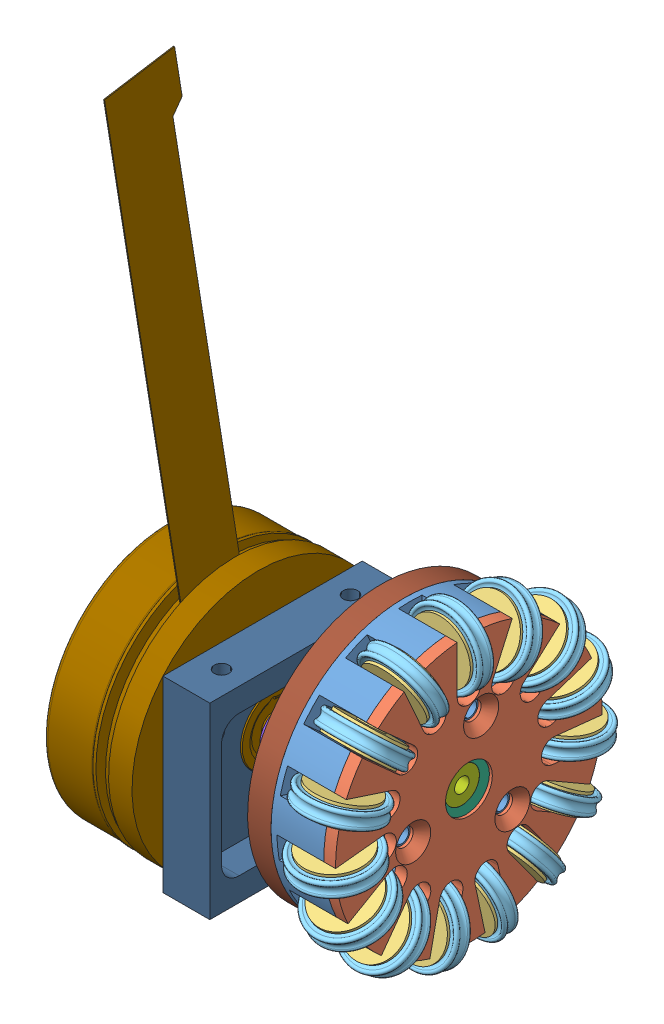
SolidWorks assembly drive_right, configuration Default. Lengths in mm.
Overall size (56.39 137.4 77.93).
69 component instances, 11 part files, 22 mates.
Components (placement in the parent):
- wheel_hub_flat_back-1: wheel_hub_flat_back [Default] at (-31.4027 -2.3485 15.5279) size (9 45.5 45.5)
- wheel_cover-1: wheel_cover [Default] at (-22.4027 -2.3485 15.5279) size (2 45.41 45.5)
- wheel_roller_asm-1: wheel_roller_asm [Default] at (-3.0698 37.2715 -2.2573) x (0.742932 0.669367 0) z (0 0 1) size (12.8 12.8 6)
  - wheel_roller_hub-1: wheel_roller_hub [Default] at (-28.6925 -1.096 17.7852) size (10.4 10.4 3.8)
  - wheel_roller_pin-1: wheel_roller_pin [Default] at (-28.6925 -1.096 14.7852) size (2.5 2.5 6)
  - xring_109-1: xring_109 [Default] at (-28.6925 -1.096 17.7852) size (12.8 12.8 2.6)
- wheel_roller_asm-2: wheel_roller_asm [Default] at (-3.0698 41.0801 15.3952) x (0.742932 0.611497 0.272256) z (0 -0.406737 0.913545) size (12.8 12.8 6)
  - wheel_roller_hub-1: wheel_roller_hub [Default] at (-28.6925 -1.096 17.7852) size (10.4 10.4 3.8)
  - wheel_roller_pin-1: wheel_roller_pin [Default] at (-28.6925 -1.096 14.7852) size (2.5 2.5 6)
  - xring_109-1: xring_109 [Default] at (-28.6925 -1.096 17.7852) size (12.8 12.8 2.6)
- wheel_roller_asm-3: wheel_roller_asm [Default] at (-3.0698 37.3795 33.0707) x (0.742932 0.447894 0.497437) z (0 -0.743145 0.669131) size (12.8 12.8 6)
  - wheel_roller_hub-1: wheel_roller_hub [Default] at (-28.6925 -1.096 17.7852) size (10.4 10.4 3.8)
  - wheel_roller_pin-1: wheel_roller_pin [Default] at (-28.6925 -1.096 14.7852) size (2.5 2.5 6)
  - xring_109-1: xring_109 [Default] at (-28.6925 -1.096 17.7852) size (12.8 12.8 2.6)
- wheel_roller_asm-4: wheel_roller_asm [Default] at (-3.0698 26.8095 47.7129) x (0.742932 0.206846 0.636606) z (0 -0.951057 0.309017) size (12.8 12.8 6)
  - wheel_roller_hub-1: wheel_roller_hub [Default] at (-28.6925 -1.096 17.7852) size (10.4 10.4 3.8)
  - wheel_roller_pin-1: wheel_roller_pin [Default] at (-28.6925 -1.096 14.7852) size (2.5 2.5 6)
  - xring_109-1: xring_109 [Default] at (-28.6925 -1.096 17.7852) size (12.8 12.8 2.6)
- wheel_roller_asm-5: wheel_roller_asm [Default] at (-3.0698 11.1979 56.79) x (0.742932 -0.069968 0.6657) z (0 -0.994522 -0.104528) size (12.8 12.8 6)
  - wheel_roller_hub-1: wheel_roller_hub [Default] at (-28.6925 -1.096 17.7852) size (10.4 10.4 3.8)
  - wheel_roller_pin-1: wheel_roller_pin [Default] at (-28.6925 -1.096 14.7852) size (2.5 2.5 6)
  - xring_109-1: xring_109 [Default] at (-28.6925 -1.096 17.7852) size (12.8 12.8 2.6)
- wheel_roller_asm-6: wheel_roller_asm [Default] at (-3.0698 -6.7561 58.7325) x (0.742932 -0.334684 0.579689) z (0 -0.866025 -0.5) size (12.8 12.8 6)
  - wheel_roller_hub-1: wheel_roller_hub [Default] at (-28.6925 -1.096 17.7852) size (10.4 10.4 3.8)
  - wheel_roller_pin-1: wheel_roller_pin [Default] at (-28.6925 -1.096 14.7852) size (2.5 2.5 6)
  - xring_109-1: xring_109 [Default] at (-28.6925 -1.096 17.7852) size (12.8 12.8 2.6)
- wheel_roller_asm-7: wheel_roller_asm [Default] at (-3.0698 -23.9479 53.2045) x (0.742932 -0.541529 0.393444) z (0 -0.587785 -0.809017) size (12.8 12.8 6)
  - wheel_roller_hub-1: wheel_roller_hub [Default] at (-28.6925 -1.096 17.7852) size (10.4 10.4 3.8)
  - wheel_roller_pin-1: wheel_roller_pin [Default] at (-28.6925 -1.096 14.7852) size (2.5 2.5 6)
  - xring_109-1: xring_109 [Default] at (-28.6925 -1.096 17.7852) size (12.8 12.8 2.6)
- wheel_roller_asm-8: wheel_roller_asm [Default] at (-3.0698 -37.405 41.162) x (0.742932 -0.65474 0.139169) z (0 -0.207912 -0.978148) size (12.8 12.8 6)
  - wheel_roller_hub-1: wheel_roller_hub [Default] at (-28.6925 -1.096 17.7852) size (10.4 10.4 3.8)
  - wheel_roller_pin-1: wheel_roller_pin [Default] at (-28.6925 -1.096 14.7852) size (2.5 2.5 6)
  - xring_109-1: xring_109 [Default] at (-28.6925 -1.096 17.7852) size (12.8 12.8 2.6)
- wheel_roller_asm-9: wheel_roller_asm [Default] at (-3.0698 -44.8005 24.687) x (0.742932 -0.65474 -0.139169) z (0 0.207912 -0.978148) size (12.8 12.8 6)
  - wheel_roller_hub-1: wheel_roller_hub [Default] at (-28.6925 -1.096 17.7852) size (10.4 10.4 3.8)
  - wheel_roller_pin-1: wheel_roller_pin [Default] at (-28.6925 -1.096 14.7852) size (2.5 2.5 6)
  - xring_109-1: xring_109 [Default] at (-28.6925 -1.096 17.7852) size (12.8 12.8 2.6)
- wheel_roller_asm-10: wheel_roller_asm [Default] at (-3.0698 -44.8557 6.6284) x (0.742932 -0.541529 -0.393444) z (0 0.587785 -0.809017) size (12.8 12.8 6)
  - wheel_roller_hub-1: wheel_roller_hub [Default] at (-28.6925 -1.096 17.7852) size (10.4 10.4 3.8)
  - wheel_roller_pin-1: wheel_roller_pin [Default] at (-28.6925 -1.096 14.7852) size (2.5 2.5 6)
  - xring_109-1: xring_109 [Default] at (-28.6925 -1.096 17.7852) size (12.8 12.8 2.6)
- wheel_roller_asm-11: wheel_roller_asm [Default] at (-3.0698 -37.561 -9.8914) x (0.742932 -0.334684 -0.579689) z (0 0.866025 -0.5) size (12.8 12.8 6)
  - wheel_roller_hub-1: wheel_roller_hub [Default] at (-28.6925 -1.096 17.7852) size (10.4 10.4 3.8)
  - wheel_roller_pin-1: wheel_roller_pin [Default] at (-28.6925 -1.096 14.7852) size (2.5 2.5 6)
  - xring_109-1: xring_109 [Default] at (-28.6925 -1.096 17.7852) size (12.8 12.8 2.6)
- wheel_roller_asm-12: wheel_roller_asm [Default] at (-3.0698 -24.1777 -22.016) x (0.742932 -0.069968 -0.6657) z (0 0.994522 -0.104528) size (12.8 12.8 6)
  - wheel_roller_hub-1: wheel_roller_hub [Default] at (-28.6925 -1.096 17.7852) size (10.4 10.4 3.8)
  - wheel_roller_pin-1: wheel_roller_pin [Default] at (-28.6925 -1.096 14.7852) size (2.5 2.5 6)
  - xring_109-1: xring_109 [Default] at (-28.6925 -1.096 17.7852) size (12.8 12.8 2.6)
- wheel_roller_asm-13: wheel_roller_asm [Default] at (-3.0698 -7.02 -27.6489) x (0.742932 0.206846 -0.636606) z (0 0.951057 0.309017) size (12.8 12.8 6)
  - wheel_roller_hub-1: wheel_roller_hub [Default] at (-28.6925 -1.096 17.7852) size (10.4 10.4 3.8)
  - wheel_roller_pin-1: wheel_roller_pin [Default] at (-28.6925 -1.096 14.7852) size (2.5 2.5 6)
  - xring_109-1: xring_109 [Default] at (-28.6925 -1.096 17.7852) size (12.8 12.8 2.6)
- wheel_roller_asm-14: wheel_roller_asm [Default] at (-3.0698 10.9455 -25.8162) x (0.742932 0.447894 -0.497437) z (0 0.743145 0.669131) size (12.8 12.8 6)
  - wheel_roller_hub-1: wheel_roller_hub [Default] at (-28.6925 -1.096 17.7852) size (10.4 10.4 3.8)
  - wheel_roller_pin-1: wheel_roller_pin [Default] at (-28.6925 -1.096 14.7852) size (2.5 2.5 6)
  - xring_109-1: xring_109 [Default] at (-28.6925 -1.096 17.7852) size (12.8 12.8 2.6)
- wheel_roller_asm-15: wheel_roller_asm [Default] at (-3.0698 26.6123 -16.8346) x (0.742932 0.611497 -0.272256) z (0 0.406737 0.913545) size (12.8 12.8 6)
  - wheel_roller_hub-1: wheel_roller_hub [Default] at (-28.6925 -1.096 17.7852) size (10.4 10.4 3.8)
  - wheel_roller_pin-1: wheel_roller_pin [Default] at (-28.6925 -1.096 14.7852) size (2.5 2.5 6)
  - xring_109-1: xring_109 [Default] at (-28.6925 -1.096 17.7852) size (12.8 12.8 2.6)
- MF126ZZ-1: MF126ZZ [Default] at (-21.6027 -2.3485 15.5279) x (-1 0 0) z (0 0.924225 0.381849) size (4 13.6 13.6)
- MF126ZZ-2: MF126ZZ [Default] at (-31.4027 -2.3485 15.5279) size (4 13.6 13.6)
- wheel_rod-1: wheel_rod [Default] at (-21.6027 -2.3485 15.5279) x (-1 0 0) z (0 0.924225 0.381849) size (23 8 8)
- Metric - Spur gear 0.5M 20T 20PA 3FW ---S20O8H8L4N-2: Metric - Spur gear 0.5M 20T 20PA 3FW ---S20O8H8L4N [Metric - Spur gear 0.5M 20T 20PA 3FW ---S20O8H8L4N] at (-35.4027 2.1015 27.209) x (1 0 0) z (0 0.134505 0.990913) size (8 10.9 10.9)
- EC45fl-200142-1: EC45fl-200142 [Default] at (-44.6027 2.1015 27.209) x (-1 0 0) z (0 -0.158938 0.987289) size (46.9 124.1 43.2)
- motor_mount_right-1: motor_mount_right [Default] at (-36.6027 -15.7485 9.5279) x (-1 0 0) z (0 0 -1) size (8 32 34)
- DIN - Internal spur gear 0.5M 70T 20PA 4FW ---S70S45,5OD 1AF-2: DIN - Internal spur gear 0.5M 70T 20PA 4FW ---S70S45,5OD 1AF [DIN - Internal spur gear 0.5M 70T 20PA 4FW ---S70S45,5OD 1AF] at (-31.4027 -2.3485 15.5279) x (-1 0 0) z (0 -0.207912 -0.978148) size (4 45.5 45.5)
Mates (geometry in assembly coordinates):
- Width1: width anti-aligned: plane of wheel_hub_flat_back-1 through (-30.4027 12.1015 17.5279) normal (0 0 -1); plane of wheel_hub_flat_back-1 through (-30.4027 20.4015 13.5279) normal (0 0 1); plane of wheel_roller_asm-1/wheel_roller_hub-1 through (-24.5229 18.2173 17.4279) normal (0 0 1); plane of wheel_roller_asm-1/wheel_roller_hub-1 through (-24.9915 18.7374 13.6279) normal (0 0 -1)
- Distance1: distance = 0 mm aligned: plane of wheel_hub_flat_back-1 through (-22.4027 -2.3485 15.5279) normal (1 0 0); cylinder of wheel_roller_asm-1/wheel_roller_pin-1 through (-23.6527 17.2515 18.5279) axis (0 0 -1) radius 1.25
- Distance2: distance = 0 mm anti-aligned: cylinder of wheel_roller_asm-1/wheel_roller_pin-1 through (-23.6527 17.2515 18.5279) axis (0 0 -1) radius 1.25; plane of wheel_hub_flat_back-1 through (-24.9027 18.5015 18.5279) normal (0 -1 0)
- Concentric2: concentric aligned: cylinder of wheel_hub_flat_back-1 through (-22.4027 7.433 13.4488) axis (1 0 0) radius 1.25; cylinder of wheel_cover-1 through (-22.4037 7.433 13.4488) axis (1 0 0) radius 1.5
- Concentric3: concentric aligned: cylinder of wheel_cover-1 through (-22.4037 7.433 13.4488) axis (1 0 0) radius 1.5; cylinder of wheel_hub_flat_back-1 through (-22.4027 7.433 13.4488) axis (1 0 0) radius 1.25
- Coincident1: coincident anti-aligned: plane of wheel_hub_flat_back-1 through (-22.4027 -2.3485 15.5279) normal (1 0 0); plane of wheel_cover-1 through (-22.4027 -2.3485 15.5279) normal (-1 0 0)
- Concentric4: concentric aligned: cylinder of wheel_hub_flat_back-1 through (-22.4027 -2.3485 15.5279) axis (-1 0 0) radius 6.005; cylinder of MF126ZZ-2 through (-31.4027 -2.3485 15.5279) axis (-1 0 0) radius 6
- Coincident2: coincident anti-aligned: plane of wheel_hub_flat_back-1 through (-30.6027 -2.3485 15.5279) normal (-1 0 0); plane of MF126ZZ-2 through (-30.6027 4.4515 15.5279) normal (1 0 0)
- Concentric5: concentric anti-aligned: cylinder of wheel_hub_flat_back-1 through (-22.4027 -2.3485 15.5279) axis (-1 0 0) radius 6.005; cylinder of MF126ZZ-1 through (-21.6027 -2.3485 15.5279) axis (1 0 0) radius 6
- Coincident3: coincident anti-aligned: plane of wheel_hub_flat_back-1 through (-22.4027 -2.3485 15.5279) normal (1 0 0); plane of MF126ZZ-1 through (-22.4027 -4.9451 21.8126) normal (-1 0 0)
- Concentric6: concentric aligned: cylinder of MF126ZZ-1 through (-21.6027 -2.3485 15.5279) axis (1 0 0) radius 3; cylinder of wheel_rod-1 through (-21.6027 -2.3485 15.5279) axis (1 0 0) radius 2.99
- Coincident4: coincident anti-aligned: plane of MF126ZZ-2 through (-31.4027 0.6515 15.5279) normal (-1 0 0); plane of wheel_rod-1 through (-31.4027 -3.8759 19.2248) normal (1 0 0)
- Concentric13: concentric aligned: cylinder of Metric - Spur gear 0.5M 20T 20PA 3FW ---S20O8H8L4N-2 through (-40.4028 2.1015 27.209) axis (1 0 0) radius 4; cylinder of EC45fl-200142-1 through (-42.1027 2.1015 27.209) axis (1 0 0) radius 2
- Concentric16: concentric anti-aligned: cylinder of wheel_rod-1 through (-21.6027 -2.3485 15.5279) axis (1 0 0) radius 3; cylinder of motor_mount_right-1 through (-36.6017 -2.3485 15.5279) axis (-1 0 0) radius 3
- Coincident6: coincident anti-aligned: plane of wheel_rod-1 through (-36.6027 -3.4941 18.3006) normal (-1 0 0); plane of motor_mount_right-1 through (-36.6027 -15.7485 9.5279) normal (1 0 0)
- Concentric17: concentric anti-aligned: cylinder of EC45fl-200142-1 through (-44.6027 2.1015 27.209) axis (1 0 0) radius 6; cylinder of motor_mount_right-1 through (-36.6017 2.1015 27.209) axis (-1 0 0) radius 6.1
- Concentric18: concentric anti-aligned: cylinder of EC45fl-200142-1 through (-48.6027 6.0175 37.4883) axis (1 0 0) radius 1.25; cylinder of motor_mount_right-1 through (-36.6017 6.0175 37.4883) axis (-1 0 0) radius 1.5
- Coincident7: coincident anti-aligned: plane of EC45fl-200142-1 through (-44.6027 2.1015 27.209) normal (1 0 0); plane of motor_mount_right-1 through (-44.6027 -15.7485 9.5279) normal (-1 0 0)
- Parallel1: parallel anti-aligned: plane of motor_mount_right-1 through (-44.6027 -15.7485 9.5279) normal (0 -1 0); plane of assembly through (0 0 0) normal (0 1 0)
- Concentric20: concentric: cylinder of wheel_hub_flat_back-1 through (-31.4027 17.9481 11.2137) axis (-1 0 0) radius 0.8; cylinder of DIN - Internal spur gear 0.5M 70T 20PA 4FW ---S70S45,5OD 1AF-2 through (-31.4017 17.9481 11.2137) axis (-1 0 0) radius 1
- Concentric21: concentric anti-aligned: cylinder of wheel_hub_flat_back-1 through (-22.4027 -2.3485 15.5279) axis (-1 0 0) radius 22.75; cylinder of DIN - Internal spur gear 0.5M 70T 20PA 4FW ---S70S45,5OD 1AF-2 through (-21.4027 -2.3485 15.5279) axis (1 0 0) radius 22.75
- Coincident10: coincident anti-aligned: plane of wheel_hub_flat_back-1 through (-31.4027 -2.3485 15.5279) normal (-1 0 0); plane of DIN - Internal spur gear 0.5M 70T 20PA 4FW ---S70S45,5OD 1AF-2 through (-31.4027 1.186 32.1564) normal (1 0 0)
